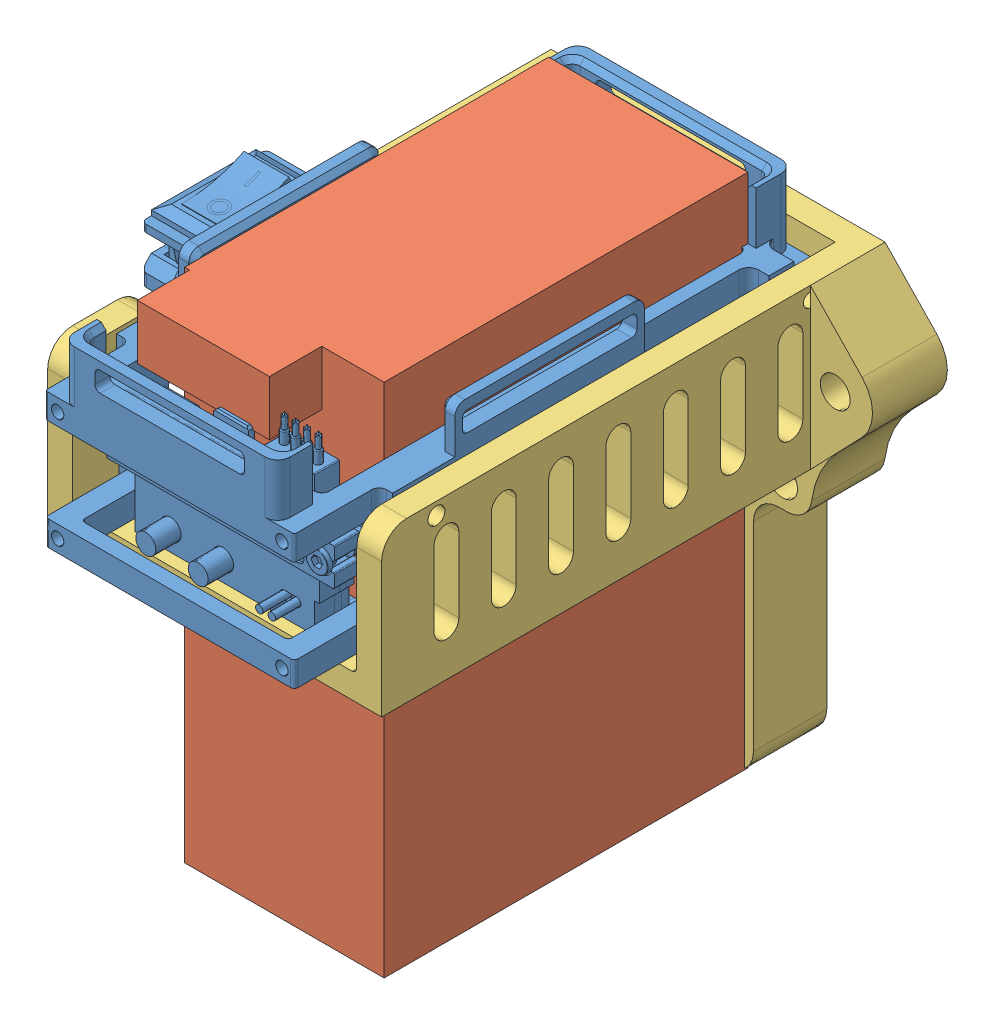
SolidWorks assembly 电池, configuration 默认. Lengths in mm.
Overall size (92 104.41 110).
3 component instances, 3 part files, 5 mates.
Components (placement in the parent):
- 大疆电池座-1: 大疆电池座 [开关位置-默认] at (-47.0246 -14.4693 0) size (69.4 39.5 103.5)
- TB47电池-1: TB47电池 [默认] at (-47.0246 -26.8105 -7.75) x (-1 0 0) z (0 0 -1) size (40 103.5 83.5)
- 电池架-1: 电池架 [默认] at (-47.0246 -19.4693 0.75) x (1 0 0) z (0 1 0) size (92 101 92)
Mates (geometry in assembly coordinates):
- 宽度2: width anti-aligned: plane of 大疆电池座-1 through (-68.0246 7.5307 35.25) normal (1 0 0); plane of TB47电池-1 through (-26.0246 7.5307 35.25) normal (-1 0 0); plane of 大疆电池座-1 through (-67.0246 24.9395 -44.25) normal (-1 0 0); plane of TB47电池-1 through (-27.0246 24.9395 -44.25) normal (1 0 0)
- 重合4: coincident anti-aligned: plane of 大疆电池座-1 through (-164.3419 12.5307 -44.25) normal (0 0 1); plane of TB47电池-1 through (-27.0246 24.9395 -44.25) normal (0 0 -1)
- 同心3: concentric anti-aligned: cylinder of 大疆电池座-1 through (-19.3246 10.0307 31.75) axis (1 0 0) radius 1.25; cylinder of 电池架-1 through (-13.5246 10.0307 31.75) axis (-1 0 0) radius 1.7
- 同心4: concentric anti-aligned: cylinder of 大疆电池座-1 through (-19.3246 10.0307 -43.25) axis (1 0 0) radius 1.25; cylinder of 电池架-1 through (-13.5246 10.0307 -43.25) axis (-1 0 0) radius 1.4
- 宽度3: width aligned: plane of 电池架-1 through (-75.5246 12.5307 59.75) normal (1 0 0); plane of 电池架-1 through (-18.5246 12.5307 59.75) normal (-1 0 0); plane of 大疆电池座-1 through (-25.3746 -106.0375 -49.25) normal (1 0 0); plane of 大疆电池座-1 through (-68.6746 -106.0375 -49.25) normal (-1 0 0)
